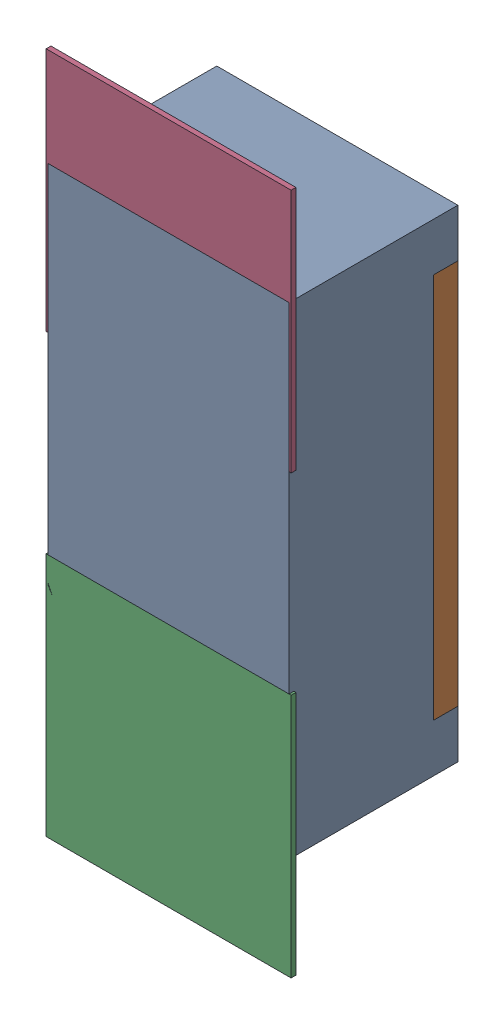
SolidWorks assembly R37, configuration Défaut. Lengths in mm.
Overall size (0.51 1.42 0.35).
5 component instances, 2 part files, 0 mates.
Components (placement in the parent):
- R0402-1: R0402 [Défaut] at (21.717 -11.9294 -2.0818) x (0 1 0) z (0 0 -1) size (1 0.5 0.35)
- 6504207776-1: 6504207776 [Défaut] at (21.7172 -12.3864 -2.0918) size (0.51 0.51 0.01)
  - Extruded-1: Extruded [Défaut] at origin size (0.51 0.51 0.01)
- 6504207776-2: 6504207776 [Défaut] at (21.7172 -11.4794 -2.0918) size (0.51 0.51 0.01)
  - Extruded-1: Extruded [Défaut] at origin size (0.51 0.51 0.01)
